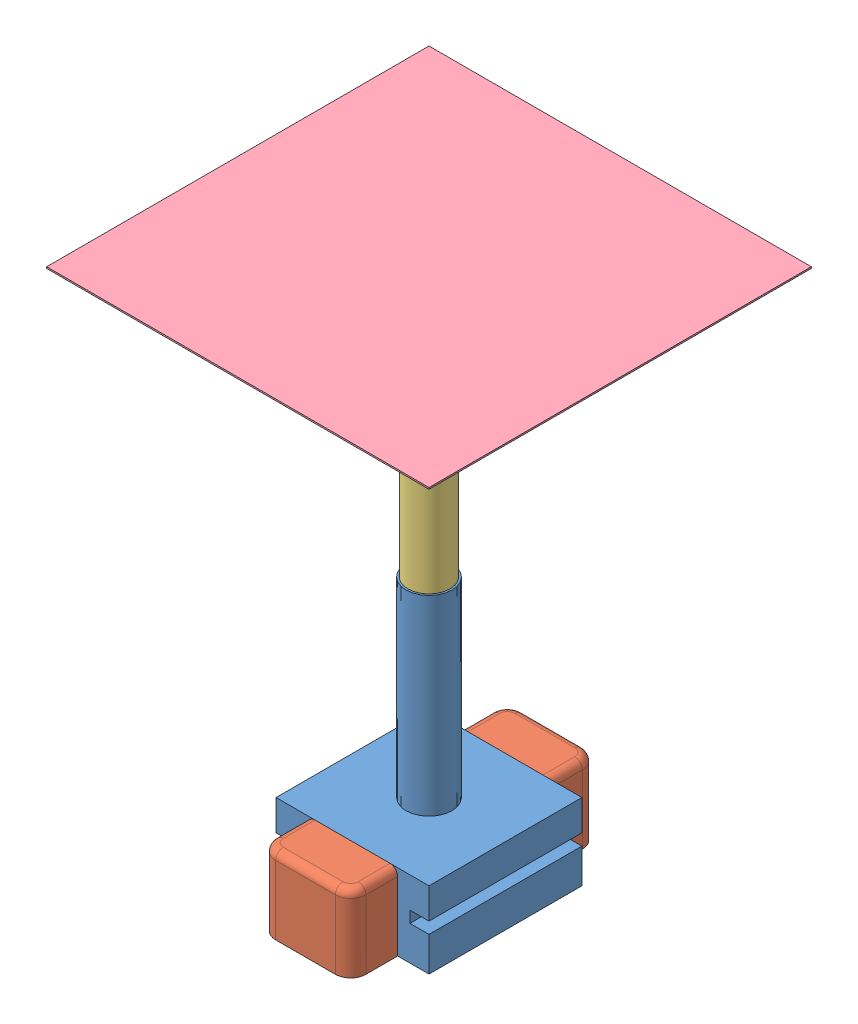
SolidWorks assembly pole undep, configuration Default. Lengths in mm.
Overall size (1000 1402.21 1000).
11 component instances, 6 part files, 12 mates.
Components (placement in the parent):
- pilon-1: pilon [Default] at (750.6878 634.4701 2074.8363) size (400 700 400)
- fix-1: fix [Default] at (704.1878 324.4701 2336.3363) size (236 530 123)
  - screw - Copy-1: screw - Copy [Default] at origin size (83 330 83) (hidden)
  - Part3^fix-1: Part3^fix [Default] at origin size (236 200 123) (virtual)
  - screw2 - Copy - Copy-1: screw2 - Copy - Copy [Default] at (97.0846 0 0) size (83 330 83) (hidden)
- fix-2: fix [Default] at (797.1878 324.4701 1813.3363) x (-1 0 0) z (0 0 -1) size (236 530 123)
  - screw - Copy-1: screw - Copy [Default] at origin size (83 330 83) (hidden)
  - Part3^fix-1: Part3^fix [Default] at origin size (236 200 123) (virtual)
  - screw2 - Copy - Copy-1: screw2 - Copy - Copy [Default] at (97.0846 0 0) size (83 330 83) (hidden)
- pilon2-1: pilon2 [Default] at (750.6878 1322.6821 2074.8363) x (-0.067113 0 0.997745) z (-0.997745 0 -0.067113) size (110 500 110)
- cap-2: cap [Default] at (750.6878 1822.6821 2074.8363) x (0 0 1) z (-1 0 0) size (1000 264 1000)
Mates (geometry in assembly coordinates):
- Coincident2: coincident: plane of pilon-1 through (950.6878 834.4701 2274.8363) normal (0 0 1); plane of fix-1/Part3^fix-1 through (632.6878 834.4701 2274.8363) normal (0 0 -1)
- Width1: width: plane of pilon-1 through (950.6878 834.4701 2274.8363) normal (1 0 0); plane of pilon-1 through (550.6878 834.4701 2274.8363) normal (-1 0 0); plane of fix-1/Part3^fix-1 through (868.6878 834.4701 2357.8363) normal (1 0 0); plane of fix-1/Part3^fix-1 through (632.6878 834.4701 2357.8363) normal (-1 0 0)
- Coincident3: coincident: plane of pilon-1 through (750.6878 634.4701 2074.8363) normal (0 -1 0); plane of fix-1/Part3^fix-1 through (828.6878 634.4701 2357.8363) normal (0 -1 0)
- Coincident4: coincident: plane of pilon-1 through (950.6878 834.4701 1874.8363) normal (0 0 -1); plane of fix-2/Part3^fix-1 through (868.6878 834.4701 1874.8363) normal (0 0 1)
- Width2: width: plane of pilon-1 through (950.6878 834.4701 2274.8363) normal (1 0 0); plane of pilon-1 through (550.6878 834.4701 2274.8363) normal (-1 0 0); plane of fix-2/Part3^fix-1 through (868.6878 834.4701 1791.8363) normal (1 0 0); plane of fix-2/Part3^fix-1 through (632.6878 834.4701 1791.8363) normal (-1 0 0)
- Coincident5: coincident: plane of pilon-1 through (750.6878 634.4701 2074.8363) normal (0 -1 0); plane of fix-2/Part3^fix-1 through (672.6878 634.4701 1791.8363) normal (0 -1 0)
- Concentric1: concentric: cylinder of pilon-1 through (750.6878 2834.4701 2074.8363) axis (0 -1 0) radius 50; cylinder of ? through (750.6878 2784.4701 2074.8363) axis (0 1 0) radius 45
- Coincident6: coincident: plane of pilon-1 through (750.6878 2834.4701 2074.8363) normal (0 1 0); plane of ? through (750.6878 2834.4701 2074.8363) normal (0 -1 0)
- Concentric2: concentric: cylinder of pilon-1 through (750.6878 1334.4701 2074.8363) axis (0 -1 0) radius 55; cylinder of pilon2-1 through (750.6878 1822.6821 2074.8363) axis (0 -1 0) radius 55
- Concentric3: concentric: cylinder of pilon2-1 through (750.6878 1822.6821 2074.8363) axis (0 -1 0) radius 50; cylinder of cap-2 through (750.6878 1772.6821 2074.8363) axis (0 1 0) radius 45
- Coincident7: coincident: plane of pilon2-1 through (750.6878 1822.6821 2074.8363) normal (0 1 0); plane of cap-2 through (750.6878 1822.6821 2074.8363) normal (0 -1 0)
- Parallel2: parallel: plane of pilon-1 through (950.6878 834.4701 2274.8363) normal (1 0 0); plane of cap-2 through (1250.6878 2036.6821 1574.8363) normal (1 0 0)
